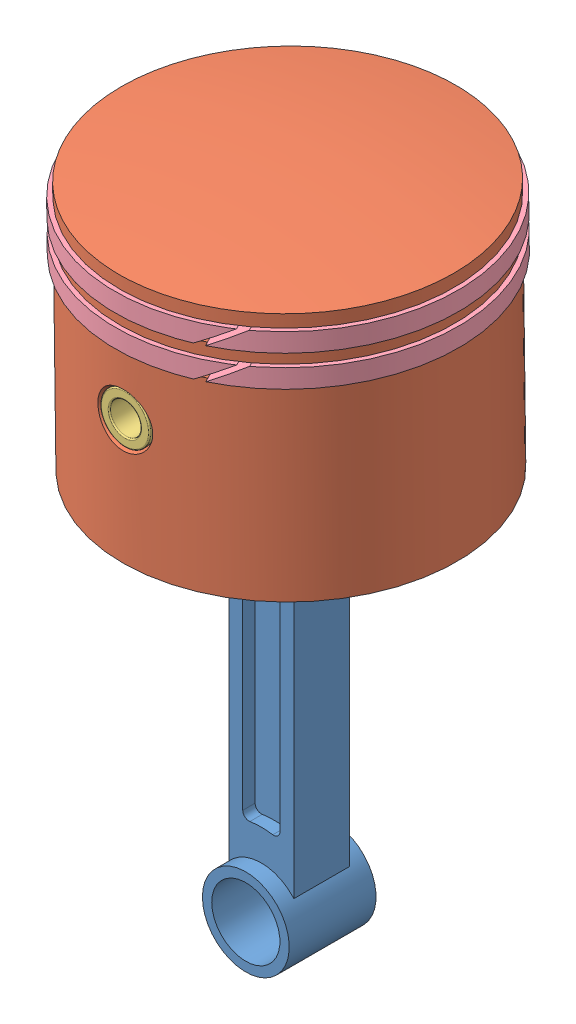
SolidWorks assembly Piston assembly, configuration Default. Lengths in mm.
Overall size (74.22 109.35 74.12).
5 component instances, 4 part files, 8 mates.
Components (placement in the parent):
- Connecting Rod for piston-1: Connecting Rod for piston [Default] at (44.926 1.0608 72.3922) size (14 94 14)
- Piston corrected-1: Piston corrected [Default] at (45.1907 61.0625 72.3922) x (0.999912 0.013234 0) z (0 0 1) size (53.6 42 53.6)
- Connectoing rod-1: Connectoing rod [Default] at (44.926 81.0608 72.3922) x (1 0 0) z (0 -1 0) size (8 53 8)
- Piston Ring-1: Piston Ring [Default] at (44.7275 96.0595 72.3922) x (0.888214 0.011756 -0.459279) z (0.459239 0.006078 0.888292) size (55 3 55)
- Piston Ring-2: Piston Ring [Default] at (44.7937 91.0599 72.3922) x (0.888214 0.011756 -0.459279) z (0.459239 0.006078 0.888292) size (55 3 55)
Mates (geometry in assembly coordinates):
- Concentric1: concentric anti-aligned: cylinder of Piston corrected-1 through (44.926 81.0608 45.5922) axis (0 0 1) radius 4; cylinder of Connectoing rod-1 through (44.926 81.0608 98.8922) axis (0 0 -1) radius 4
- Width1: width: plane of Connectoing rod-1 through (44.926 81.0608 98.8922) normal (0 0 1); plane of Piston corrected-1 through (44.926 81.0608 45.8922) normal (0 0 -1); cylinder of Connectoing rod-1 through (44.3069 127.8362 72.3922) axis (-0.013234 0.999912 0) radius 26.8
- Concentric2: concentric aligned: cylinder of Connecting Rod for piston-1 through (44.926 81.0608 79.3922) axis (0 0 -1) radius 4; cylinder of Connectoing rod-1 through (44.926 81.0608 98.8922) axis (0 0 -1) radius 4
- Width2: width: plane of Connecting Rod for piston-1 through (44.926 81.0608 65.3922) normal (0 0 -1); plane of Piston corrected-1 through (44.926 81.0608 79.3922) normal (0 0 1); cylinder of Connecting Rod for piston-1 through (44.7937 91.0599 72.3922) axis (0.013234 -0.999912 0) radius 22
- Concentric3: concentric anti-aligned: cylinder of Piston corrected-1 through (44.3069 127.8362 72.3922) axis (-0.013234 0.999912 0) radius 23.8; cylinder of Piston Ring-1 through (44.6878 99.0592 72.3922) axis (0.013234 -0.999912 0) radius 23.8
- Width3: width anti-aligned: plane of Piston Ring-1 through (44.6878 99.0592 72.3922) normal (-0.013234 0.999912 0); plane of Piston corrected-1 through (44.7275 96.0595 72.3922) normal (0.013234 -0.999912 0); plane of Piston Ring-1 through (44.6878 99.0592 72.3922) normal (0.013234 -0.999912 0); plane of Piston corrected-1 through (44.7275 96.0595 72.3922) normal (-0.013234 0.999912 0)
- Concentric4: concentric anti-aligned: cylinder of Piston corrected-1 through (44.3069 127.8362 72.3922) axis (-0.013234 0.999912 0) radius 23.8; cylinder of Piston Ring-2 through (44.754 94.0596 72.3922) axis (0.013234 -0.999912 0) radius 23.8
- Width4: width anti-aligned: plane of Piston Ring-2 through (44.754 94.0596 72.3922) normal (-0.013234 0.999912 0); plane of Piston corrected-1 through (44.7937 91.0599 72.3922) normal (0.013234 -0.999912 0); plane of Piston Ring-2 through (44.754 94.0596 72.3922) normal (0.013234 -0.999912 0); plane of Piston corrected-1 through (44.7937 91.0599 72.3922) normal (-0.013234 0.999912 0)
